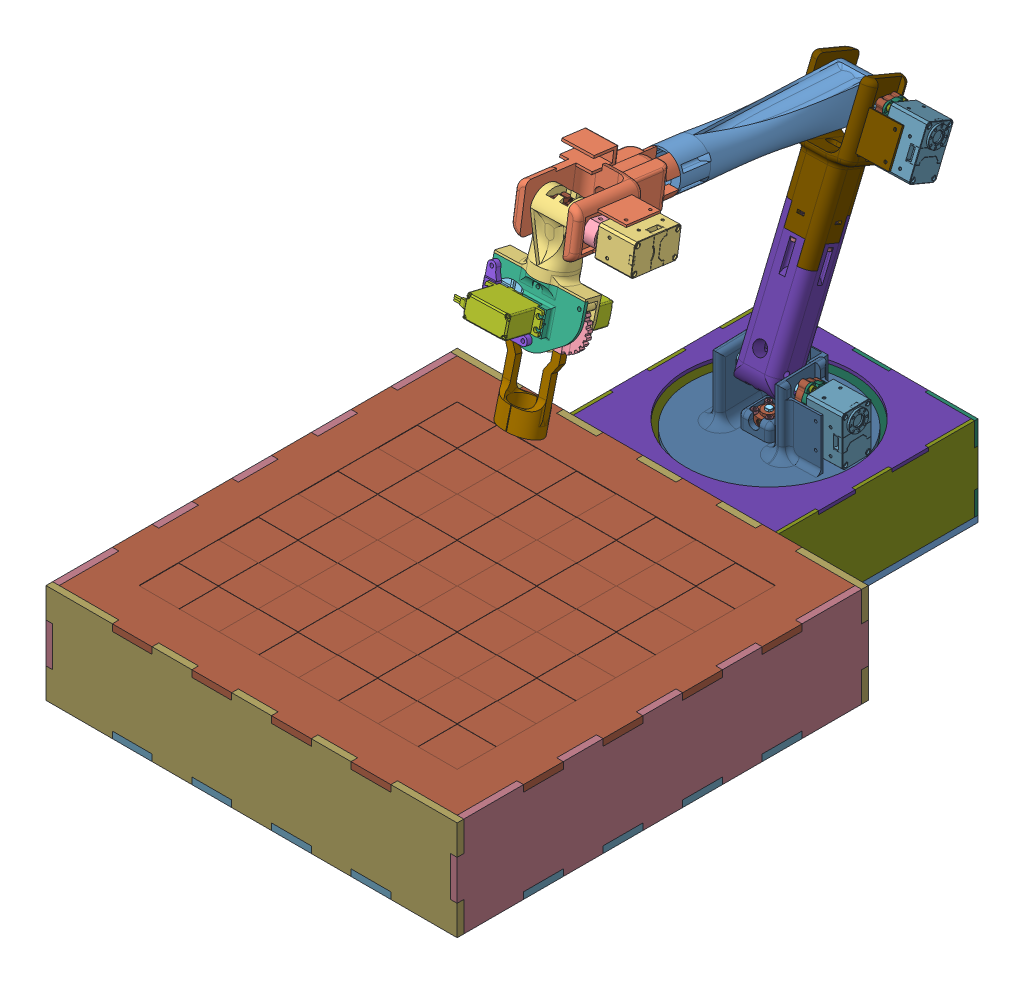
SolidWorks assembly FULL_ASSEMBLY, configuration Défaut. Lengths in mm.
Overall size (393.7 394.45 606.92).
114 component instances, 35 part files, 5 mates.
Components (placement in the parent):
- ASSEMBLY_ARM_CHESS_BRAS-1: ASSEMBLY_ARM_CHESS_BRAS [Défaut] at origin size (200 394.45 403.36)
  - base_robot-1: base_robot [Défaut] at origin size (200 16 200)
  - Support_Bearing_V4-1: Support_Bearing_V4 [Défaut] at (0 16 0) x (0 0 1) z (-1 0 0) size (100 58.5 100)
  - XL430-W250-1: XL430-W250 [Défaut] at (0 42 0) x (-1 0 0) z (0 1 0) size (28.5 46.5 36.18)
  - Coupler_Joint3-1: Coupler_Joint3 [Défaut] at (0 45 0) x (-0.999605 0 0.028091) z (-0.028091 0 -0.999605) size (22.5 11 20.75)
  - shaft-1: shaft [2po] at (0 70.4 0) x (0.999605 0 -0.028091) z (0 -1 0) size (6.35 5.71 50.8)
  - M3-16mm_91292A115_TYPE 18-8 SS SOCKET HEAD CAP SCREW-1: M3-16mm_91292A115_TYPE 18-8 SS SOCKET HEAD CAP SCREW [91292A115] at (22.5 21 -30) x (0.270289 0 0.962779) z (0 1 0) size (5.5 5.5 19.25)
  - M3-16mm_91292A115_TYPE 18-8 SS SOCKET HEAD CAP SCREW-2: M3-16mm_91292A115_TYPE 18-8 SS SOCKET HEAD CAP SCREW [91292A115] at (-22.5 21 30) x (0.142923 0 0.989734) z (0 1 0) size (5.5 5.5 19.25)
  - M3-16mm_91292A115_TYPE 18-8 SS SOCKET HEAD CAP SCREW-3: M3-16mm_91292A115_TYPE 18-8 SS SOCKET HEAD CAP SCREW [91292A115] at (-22.5 21 -30) x (-0.967146 0 0.254223) z (0 1 0) size (5.5 5.5 19.25)
  - M3-16mm_91292A115_TYPE 18-8 SS SOCKET HEAD CAP SCREW-4: M3-16mm_91292A115_TYPE 18-8 SS SOCKET HEAD CAP SCREW [91292A115] at (22.5 21 30) x (0.348034 0 0.937482) z (0 1 0) size (5.5 5.5 19.25)
  - M3-NUT_90710A030_TYPE 18-8 SS THIN HEX NUT - DIN 439B-1: M3-NUT_90710A030_TYPE 18-8 SS THIN HEX NUT - DIN 439B [90710A030] at (22.5 19.4 -30) x (0.887075 0 -0.461625) z (-0.461625 0 -0.887075) size (5.5 2.19 6.35)
  - M3-NUT_90710A030_TYPE 18-8 SS THIN HEX NUT - DIN 439B-2: M3-NUT_90710A030_TYPE 18-8 SS THIN HEX NUT - DIN 439B [90710A030] at (-22.5 19.4 -30) x (0.998436 0 0.055912) z (-0.055912 0 0.998436) size (5.5 2.19 6.35)
  - M3-NUT_90710A030_TYPE 18-8 SS THIN HEX NUT - DIN 439B-3: M3-NUT_90710A030_TYPE 18-8 SS THIN HEX NUT - DIN 439B [90710A030] at (-22.5 19.4 30) x (0.076416 0 -0.997076) z (0.997076 0 0.076416) size (5.5 2.19 6.35)
  - M3-NUT_90710A030_TYPE 18-8 SS THIN HEX NUT - DIN 439B-4: M3-NUT_90710A030_TYPE 18-8 SS THIN HEX NUT - DIN 439B [90710A030] at (22.5 19.4 30) x (-0.208862 0 0.977945) z (-0.977945 0 -0.208862) size (5.5 2.19 6.35)
  - bearing-1: bearing [Default] at (0 58.1597 -32.8363) x (0.994869 0.079004 -0.063204) z (0 0.624695 0.780869) size (22.23 22.23 8.73)
  - bearing-2: bearing [Default] at (-28.437 58.1597 16.4181) x (0.188165 0.365941 0.911417) z (-0.676252 -0.624695 0.390434) size (22.23 22.23 8.73)
  - bearing-3: bearing [Default] at (28.437 58.1597 16.4181) x (0.671098 0.303827 -0.676252) z (0.676252 -0.624695 0.390434) size (22.23 22.23 8.73)
  - M2-4mm_TYPE 18-8 SS SOCKET HEAD CAP SCREW-1: M2-4mm_TYPE 18-8 SS SOCKET HEAD CAP SCREW [91292A832] at (-0.2247 43.7 -7.9968) x (0.453166 0 -0.891426) z (0 -1 0) size (3.8 3.8 6.09)
  - M2-4mm_TYPE 18-8 SS SOCKET HEAD CAP SCREW-2: M2-4mm_TYPE 18-8 SS SOCKET HEAD CAP SCREW [91292A832] at (-7.9968 43.7 0.2247) x (0.453166 0 -0.891426) z (0 -1 0) size (3.8 3.8 6.09)
  - M2-4mm_TYPE 18-8 SS SOCKET HEAD CAP SCREW-3: M2-4mm_TYPE 18-8 SS SOCKET HEAD CAP SCREW [91292A832] at (7.9968 43.7 -0.2247) x (0.453166 0 -0.891426) z (0 -1 0) size (3.8 3.8 6.09)
  - base_350W-1: base_350W [Défaut] at (-0.0002 69.5 -0.0002) x (-0.999605 0 0.028091) z (-0.028091 0 -0.999605) size (150 75 150)
  - 545548_hub-1: 545548_hub [Default] at (-39.1478 106.1015 -7.8743) x (-0.999605 0 0.028091) z (0.028091 0 0.999605) size (20.57 9.53 20.57)
    - 545548 assembly.STEP-1: 545548 assembly.STEP [Default] at origin size (20.57 9.53 20.57)
      - 545548.STEP-1: 545548.STEP [Default] at (-38.9112 12.0765 8.9709) size (20.57 9.53 20.57)
      - 632138_91375A438.STEP-1: 632138_91375A438.STEP [Default] at (-38.9112 18.109 15.0823) x (0.93363 0.358238 0) z (0 0 1) size (4.83 4.83 6.36)
  - M3-20mm_91292A123_TYPE 18-8 SS SOCKET HEAD CAP SCREW-1: M3-20mm_91292A123_TYPE 18-8 SS SOCKET HEAD CAP SCREW [91292A123] at (-6.7178 66.485 7.1063) x (1 0 0) z (0 -1 0) size (5.5 5.5 28.3)
  - M3-20mm_91292A123_TYPE 18-8 SS SOCKET HEAD CAP SCREW-2: M3-20mm_91292A123_TYPE 18-8 SS SOCKET HEAD CAP SCREW [91292A123] at (7.1063 66.485 6.7178) x (0.837169 0 0.546944) z (0 -1 0) size (5.5 5.5 28.3)
  - M3-20mm_91292A123_TYPE 18-8 SS SOCKET HEAD CAP SCREW-3: M3-20mm_91292A123_TYPE 18-8 SS SOCKET HEAD CAP SCREW [91292A123] at (-7.1063 66.485 -6.7178) x (0.839089 0 0.543994) z (0 -1 0) size (5.5 5.5 28.3)
  - M3-20mm_91292A123_TYPE 18-8 SS SOCKET HEAD CAP SCREW-4: M3-20mm_91292A123_TYPE 18-8 SS SOCKET HEAD CAP SCREW [91292A123] at (6.7178 66.485 -7.1063) x (0.837169 0 0.546944) z (0 -1 0) size (5.5 5.5 28.3)
  - M3-NUT_90710A030_TYPE 18-8 SS THIN HEX NUT - DIN 439B-5: M3-NUT_90710A030_TYPE 18-8 SS THIN HEX NUT - DIN 439B [90710A030] at (6.7178 73.6 -7.1063) x (-0.877485 0 0.479605) z (0.479605 0 0.877485) size (5.5 2.19 6.35)
  - M3-NUT_90710A030_TYPE 18-8 SS THIN HEX NUT - DIN 439B-6: M3-NUT_90710A030_TYPE 18-8 SS THIN HEX NUT - DIN 439B [90710A030] at (-7.1063 73.6 -6.7178) x (0.422721 0 0.90626) z (0.90626 0 -0.422721) size (5.5 2.19 6.35)
  - M3-NUT_90710A030_TYPE 18-8 SS THIN HEX NUT - DIN 439B-7: M3-NUT_90710A030_TYPE 18-8 SS THIN HEX NUT - DIN 439B [90710A030] at (-6.7178 73.6 7.1063) x (0.887517 0 0.460775) z (0.460775 0 -0.887517) size (5.5 2.19 6.35)
  - M3-NUT_90710A030_TYPE 18-8 SS THIN HEX NUT - DIN 439B-8: M3-NUT_90710A030_TYPE 18-8 SS THIN HEX NUT - DIN 439B [90710A030] at (7.1063 73.6 6.7178) x (0.999903 0 0.013926) z (0.013926 0 -0.999903) size (5.5 2.19 6.35)
  - XM430-W350-1: XM430-W350 [Default] at (64.9812 125 -1.5762) x (0.028091 0 0.999605) z (-0.999605 0 0.028091) size (28.5 46.5 42.4)
  - coupleur350W-1: coupleur350W [Défaut] at (42.9898 125 -0.9582) x (-0.025922 -0.385253 -0.922447) z (-0.010822 0.922811 -0.385101) size (22.5 5 22.5)
  - 545548_hub-2: 545548_hub [Default] at (18.2948 117.7261 -39.5435) x (-0.025765 -0.398399 -0.91685) z (0.011191 -0.917212 0.398242) size (20.57 9.53 20.57)
    - 545548 assembly.STEP-1: 545548 assembly.STEP [Default] at origin size (20.57 9.53 20.57)
      - 545548.STEP-1: 545548.STEP [Default] at (-38.9112 12.0765 8.9709) size (20.57 9.53 20.57)
      - 632138_91375A438.STEP-1: 632138_91375A438.STEP [Default] at (-38.9112 18.109 15.0823) x (0.93363 0.358238 0) z (0 0 1) size (4.83 4.83 6.36)
  - M3-8mm_91292A112_TYPE 18-8 SS SOCKET HEAD CAP SCREW-1: M3-8mm_91292A112_TYPE 18-8 SS SOCKET HEAD CAP SCREW [91292A112] at (34.8885 115.9482 -4.4519) x (0.026773 -0.302684 0.952715) z (-0.999605 0 0.028091) size (5.5 5.5 11.2)
  - M3-8mm_91292A112_TYPE 18-8 SS SOCKET HEAD CAP SCREW-2: M3-8mm_91292A112_TYPE 18-8 SS SOCKET HEAD CAP SCREW [91292A112] at (35.2473 121.2801 8.3148) x (0.02653 -0.328692 0.944065) z (-0.999605 0 0.028091) size (5.5 5.5 11.2)
  - M3-8mm_91292A112_TYPE 18-8 SS SOCKET HEAD CAP SCREW-3: M3-8mm_91292A112_TYPE 18-8 SS SOCKET HEAD CAP SCREW [91292A112] at (34.7387 128.7199 -9.7817) x (0.027877 0.123058 0.992008) z (-0.999605 0 0.028091) size (5.5 5.5 11.2)
  - M3-8mm_91292A112_TYPE 18-8 SS SOCKET HEAD CAP SCREW-4: M3-8mm_91292A112_TYPE 18-8 SS SOCKET HEAD CAP SCREW [91292A112] at (35.0975 134.0518 2.985) x (0.026768 -0.303288 0.952523) z (-0.999605 0 0.028091) size (5.5 5.5 11.2)
  - shaft-2: shaft [3po] at (3.5054 125 0.1514) x (-0.025765 -0.398399 -0.91685) z (-0.999605 0 0.028091) size (6.35 5.71 76.2)
  - 545548_hub-3: 545548_hub [Default] at (-12.9324 117.726 -38.6657) x (-0.025765 -0.398399 -0.91685) z (0.011191 -0.917212 0.398242) size (20.57 9.53 20.57)
    - 545548 assembly.STEP-1: 545548 assembly.STEP [Default] at origin size (20.57 9.53 20.57)
      - 545548.STEP-1: 545548.STEP [Default] at (-38.9112 12.0765 8.9709) size (20.57 9.53 20.57)
      - 632138_91375A438.STEP-1: 632138_91375A438.STEP [Default] at (-38.9112 18.109 15.0823) x (0.93363 0.358238 0) z (0 0 1) size (4.83 4.83 6.36)
  - 545548_hub-4: 545548_hub [Default] at (13.216 148.7303 32.0072) x (0.025765 0.398399 0.91685) z (0.011191 -0.917212 0.398242) size (20.57 9.53 20.57)
    - 545548 assembly.STEP-1: 545548 assembly.STEP [Default] at origin size (20.57 9.53 20.57)
      - 545548.STEP-1: 545548.STEP [Default] at (-38.9112 12.0765 8.9709) size (20.57 9.53 20.57)
      - 632138_91375A438.STEP-1: 632138_91375A438.STEP [Default] at (-38.9112 18.109 15.0823) x (0.93363 0.358238 0) z (0 0 1) size (4.83 4.83 6.36)
  - inferior_segment_1-1: inferior_segment_1 [Défaut] at (-0.023 128.302 -1.1843) x (-0.999605 0 0.028091) z (-0.025765 -0.398399 -0.91685) size (42.86 137.5 35)
  - superior350W-1: superior350W [Défaut] at (-0.9183 201.6789 -33.0436) x (-0.999605 0 0.028091) z (-0.025765 -0.398399 -0.91685) size (90 145.3 45)
  - M3-20mm_91292A123_TYPE 18-8 SS SOCKET HEAD CAP SCREW-5: M3-20mm_91292A123_TYPE 18-8 SS SOCKET HEAD CAP SCREW [91292A123] at (16.4046 240.2018 -50.2698) x (-0.885368 -0.194198 -0.422386) z (-0.011191 0.917212 -0.398242) size (5.5 5.5 28.3)
  - M3-20mm_91292A123_TYPE 18-8 SS SOCKET HEAD CAP SCREW-6: M3-20mm_91292A123_TYPE 18-8 SS SOCKET HEAD CAP SCREW [91292A123] at (-0.9941 246.2973 -35.742) x (0.744767 0.273398 0.608749) z (-0.011191 0.917212 -0.398242) size (5.5 5.5 28.3)
  - M3-20mm_91292A123_TYPE 18-8 SS SOCKET HEAD CAP SCREW-7: M3-20mm_91292A123_TYPE 18-8 SS SOCKET HEAD CAP SCREW [91292A123] at (-1.7826 234.1063 -63.7976) x (-0.892653 -0.188637 -0.409374) z (-0.011191 0.917212 -0.398242) size (5.5 5.5 28.3)
  - M3-20mm_91292A123_TYPE 18-8 SS SOCKET HEAD CAP SCREW-8: M3-20mm_91292A123_TYPE 18-8 SS SOCKET HEAD CAP SCREW [91292A123] at (-19.1813 240.2018 -49.2698) x (0.944545 0.140413 0.296849) z (-0.011191 0.917212 -0.398242) size (5.5 5.5 28.3)
  - XM430-W350-2: XM430-W350 [Default] at (58.6707 315.9714 -84.1091) x (0.025765 0.398399 0.91685) z (-0.999605 0 0.028091) size (28.5 46.5 42.4)
  - coupleur350W-2: coupleur350W [Défaut] at (36.6794 315.9714 -83.4911) x (0.004247 -0.988504 0.151137) z (-0.027768 -0.151196 -0.988114) size (22.5 5 22.5)
  - M3-8mm_91292A112_TYPE 18-8 SS SOCKET HEAD CAP SCREW-5: M3-8mm_91292A112_TYPE 18-8 SS SOCKET HEAD CAP SCREW [91292A112] at (28.5198 308.0847 -89.0583) x (0.012773 -0.890647 0.454517) z (-0.999605 0 0.028091) size (5.5 5.5 11.2)
  - M3-8mm_91292A112_TYPE 18-8 SS SOCKET HEAD CAP SCREW-6: M3-8mm_91292A112_TYPE 18-8 SS SOCKET HEAD CAP SCREW [91292A112] at (28.8453 323.8582 -77.4745) x (0.012773 -0.890647 0.454517) z (-0.999605 0 0.028091) size (5.5 5.5 11.2)
  - M3-8mm_91292A112_TYPE 18-8 SS SOCKET HEAD CAP SCREW-7: M3-8mm_91292A112_TYPE 18-8 SS SOCKET HEAD CAP SCREW [91292A112] at (28.461 321.7656 -91.15) x (0.006713 0.971024 0.238887) z (-0.999605 0 0.028091) size (5.5 5.5 11.2)
  - M3-8mm_91292A112_TYPE 18-8 SS SOCKET HEAD CAP SCREW-8: M3-8mm_91292A112_TYPE 18-8 SS SOCKET HEAD CAP SCREW [91292A112] at (28.9041 310.1773 -75.3828) x (0.012773 -0.890647 0.454517) z (-0.999605 0 0.028091) size (5.5 5.5 11.2)
  - 545548_hub-5: 545548_hub [Default] at (13.1711 355.7916 -79.8447) x (-0.004247 0.988504 -0.151137) z (-0.027768 -0.151196 -0.988114) size (20.57 9.53 20.57)
    - 545548 assembly.STEP-1: 545548 assembly.STEP [Default] at origin size (20.57 9.53 20.57)
      - 545548.STEP-1: 545548.STEP [Default] at (-38.9112 12.0765 8.9709) size (20.57 9.53 20.57)
      - 632138_91375A438.STEP-1: 632138_91375A438.STEP [Default] at (-38.9112 18.109 15.0823) x (0.93363 0.358238 0) z (0 0 1) size (4.83 4.83 6.36)
  - shaft-3: shaft [3po] at (-2.805 315.9714 -82.3815) x (0.004247 -0.988504 0.151137) z (0.999605 0 -0.028091) size (6.35 5.71 76.2)
  - segment_2-1: segment_2 [Default] at (-3.5309 315.9714 -82.3611) x (0.999605 0 -0.028091) z (0.027768 0.151196 0.988114) size (38.54 37.14 206.68)
  - 545548_hub-6: 545548_hub [Default] at (9.37 278.864 -67.9668) x (0.004247 -0.988504 0.151137) z (-0.027768 -0.151196 -0.988114) size (20.57 9.53 20.57)
    - 545548 assembly.STEP-1: 545548 assembly.STEP [Default] at origin size (20.57 9.53 20.57)
      - 545548.STEP-1: 545548.STEP [Default] at (-38.9112 12.0765 8.9709) size (20.57 9.53 20.57)
      - 632138_91375A438.STEP-1: 632138_91375A438.STEP [Default] at (-38.9112 18.109 15.0823) x (0.93363 0.358238 0) z (0 0 1) size (4.83 4.83 6.36)
  - 545548_hub-7: 545548_hub [Default] at (-15.104 355.7916 -79.0502) x (-0.004247 0.988504 -0.151137) z (-0.027768 -0.151196 -0.988114) size (20.57 9.53 20.57)
    - 545548 assembly.STEP-1: 545548 assembly.STEP [Default] at origin size (20.57 9.53 20.57)
      - 545548.STEP-1: 545548.STEP [Default] at (-38.9112 12.0765 8.9709) size (20.57 9.53 20.57)
      - 632138_91375A438.STEP-1: 632138_91375A438.STEP [Default] at (-38.9112 18.109 15.0823) x (0.93363 0.358238 0) z (0 0 1) size (4.83 4.83 6.36)
  - wrist-1: wrist [Défaut] at (1.3199 340.3959 77.3092) x (-0.999605 0 0.028091) z (-0.004247 0.988504 -0.151137) size (91 115.8 55)
  - XL430-W250-2: XL430-W250 [Défaut] at (42.7631 358.9727 199.2997) x (-0.004247 0.988504 -0.151137) z (-0.999605 0 0.028091) size (28.5 46.5 36.18)
  - Coupler_Joint3-2: Coupler_Joint3 [Défaut] at (39.7642 358.9727 199.3839) x (0.027195 0.250474 0.967741) z (0.007036 -0.968123 0.250375) size (22.5 11 20.75)
  - shaft-4: shaft [3po] at (1.6793 358.9727 200.4542) x (0.027195 0.250474 0.967741) z (-0.999605 0 0.028091) size (6.35 5.71 76.2)
  - 545548_hub-8: 545548_hub [Default] at (15.5705 340.5415 164.626) x (-0.027195 -0.250474 -0.967741) z (-0.007036 0.968123 -0.250375) size (20.57 9.53 20.57)
    - 545548 assembly.STEP-1: 545548 assembly.STEP [Default] at origin size (20.57 9.53 20.57)
      - 545548.STEP-1: 545548.STEP [Default] at (-38.9112 12.0765 8.9709) size (20.57 9.53 20.57)
      - 632138_91375A438.STEP-1: 632138_91375A438.STEP [Default] at (-38.9112 18.109 15.0823) x (0.93363 0.358238 0) z (0 0 1) size (4.83 4.83 6.36)
  - 545548_hub-9: 545548_hub [Default] at (-6.4565 360.0339 240.6164) x (0.027195 0.250474 0.967741) z (-0.007036 0.968123 -0.250375) size (20.57 9.53 20.57)
    - 545548 assembly.STEP-1: 545548 assembly.STEP [Default] at origin size (20.57 9.53 20.57)
      - 545548.STEP-1: 545548.STEP [Default] at (-38.9112 12.0765 8.9709) size (20.57 9.53 20.57)
      - 632138_91375A438.STEP-1: 632138_91375A438.STEP [Default] at (-38.9112 18.109 15.0823) x (0.93363 0.358238 0) z (0 0 1) size (4.83 4.83 6.36)
  - pince-2: pince [Défaut] at (4.0791 358.9727 200.3868) x (0.999605 0 -0.028091) z (0.007036 -0.968123 0.250375) size (89.66 95.98 180.03)
    - minisegmentServo-1: minisegmentServo [Default] at origin size (85 38 118.68)
    - gearnoMot - Copie-2: gearnoMot - Copie [Défaut] at (21.5 5 72.8) x (-0.990981 0 -0.134004) z (-0.134004 0 0.990981) size (43.87 6.5 43.87)
    - gearMot-1: gearMot [Défaut] at (-21.5 0 72.8) x (0.999997 0 0.002496) z (-0.002496 0 0.999997) size (43.87 7.5 43.44)
    - toppince-1: toppince [Défaut] at (-0.0037 10 45.8) size (85 14.77 55)
    - hs-422_sws-1: hs-422_sws [Default] at (-11.213 28.2654 82.706) x (0 0 -1) z (-1 0 0) size (19.81 42.14 58.23)
    - supportServo-1: supportServo [Défaut] at (-38.5037 13 52.8) size (46.5 6.78 48)
    - bout_pince-1: bout_pince [Défaut] at (21.4995 5 72.7083) x (-0.990981 0 -0.134004) z (-0.134004 0 0.990981) size (22.79 28.4 74.62)
    - bout_pince-2: bout_pince [Défaut] at (-21.4997 1.5 72.6719) x (0.990612 0 -0.136701) z (0.136701 0 0.990612) size (22.79 28.4 74.62)
    - BOTSUPP-1: BOTSUPP [Défaut] at (0 -3 72.8) x (-1 0 0) z (0 0 1) size (52.83 14.74 50)
    - hs-422_sws-2: hs-422_sws [Default] at (0.128 -26.2245 67.798) x (0 0 1) z (-1 0 0) size (19.81 42.14 58.23)
- CHESS_BOX-1: CHESS_BOX [Défaut] at (-1.85 88.9 296.85) size (393.7 95.25 393.7)
  - TOP_BOX-1: TOP_BOX [Défaut] at origin size (393.7 6.35 393.7)
  - BOX_SIDE_FRONT-1: BOX_SIDE_FRONT [Défaut] at (0 -41.275 190.5) x (1 0 0) z (0 -1 0) size (393.7 6.35 95.25)
  - BOX_SIDE_FRONT-2: BOX_SIDE_FRONT [Défaut] at (0 -41.275 -196.85) x (1 0 0) z (0 -1 0) size (393.7 6.35 95.25)
  - BOX_SIDE_LEFT_RIGTH-1: BOX_SIDE_LEFT_RIGTH [Défaut] at (-190.5 -41.275 0) x (0 0 1) z (0 -1 0) size (393.7 6.35 95.25)
  - BOX_SIDE_LEFT_RIGTH-2: BOX_SIDE_LEFT_RIGTH [Défaut] at (190.5 -41.275 0) x (0 0 -1) z (0 -1 0) size (393.7 6.35 95.25)
  - BOTTOM_BOX-1: BOTTOM_BOX [Défaut] at (0 -88.9 0) size (393.7 6.35 393.7)
- ARM_BOX-1: ARM_BOX [Défaut] at (0 46 96.825) size (200 80 200)
  - BOX_SIDE2-1: BOX_SIDE2 [Défaut] at origin size (200 80 3.17)
  - BOX_SIDE2-2: BOX_SIDE2 [Défaut] at (0 0 -196.825) size (200 80 3.17)
  - BOX_SIDE1-1: BOX_SIDE1 [Défaut] at (96.825 0 -96.825) x (0 0 -1) z (1 0 0) size (200 80 3.17)
  - BOX_SIDE1-2: BOX_SIDE1 [Défaut] at (-96.825 0 -96.825) x (0 0 1) z (-1 0 0) size (200 80 3.17)
  - BOX_TOP-1: BOX_TOP [Défaut] at (0 36.825 -96.825) size (200 3.17 200)
Mates (geometry in assembly coordinates):
- Coïncidente2: coincident aligned: plane of ASSEMBLY_ARM_CHESS_BRAS-1/base_robot-1 through (0 0 0) normal (0 -1 0); plane of CHESS_BOX-1/BOX_SIDE_FRONT-2 through (-198.7 0 106.35) normal (0 -1 0)
- Distance1: distance = 95 mm aligned: plane of ASSEMBLY_ARM_CHESS_BRAS-1/base_robot-1 through (100 2 100) normal (1 0 0); plane of CHESS_BOX-1/BOX_SIDE_LEFT_RIGTH-2 through (195 47.625 296.85) normal (1 0 0)
- Coïncidente4: coincident: plane of ASSEMBLY_ARM_CHESS_BRAS-1/base_robot-1 through (100 2 100) normal (1 0 0); plane of ARM_BOX-1/BOX_SIDE1-1 through (100 83.78 0) normal (1 0 0)
- Coïncidente5: coincident: line of ASSEMBLY_ARM_CHESS_BRAS-1/base_robot-1 through (100 6 -100) axis (-1 0 0); plane of ARM_BOX-1/BOX_SIDE2-2 through (0 83.78 -100) normal (0 0 -1)
- Coïncidente6: coincident anti-aligned: plane of ASSEMBLY_ARM_CHESS_BRAS-1/base_robot-1 through (0 6 0) normal (0 1 0); plane of ARM_BOX-1/BOX_SIDE2-2 through (-100 43.78 -96.825) normal (0 -1 0)
